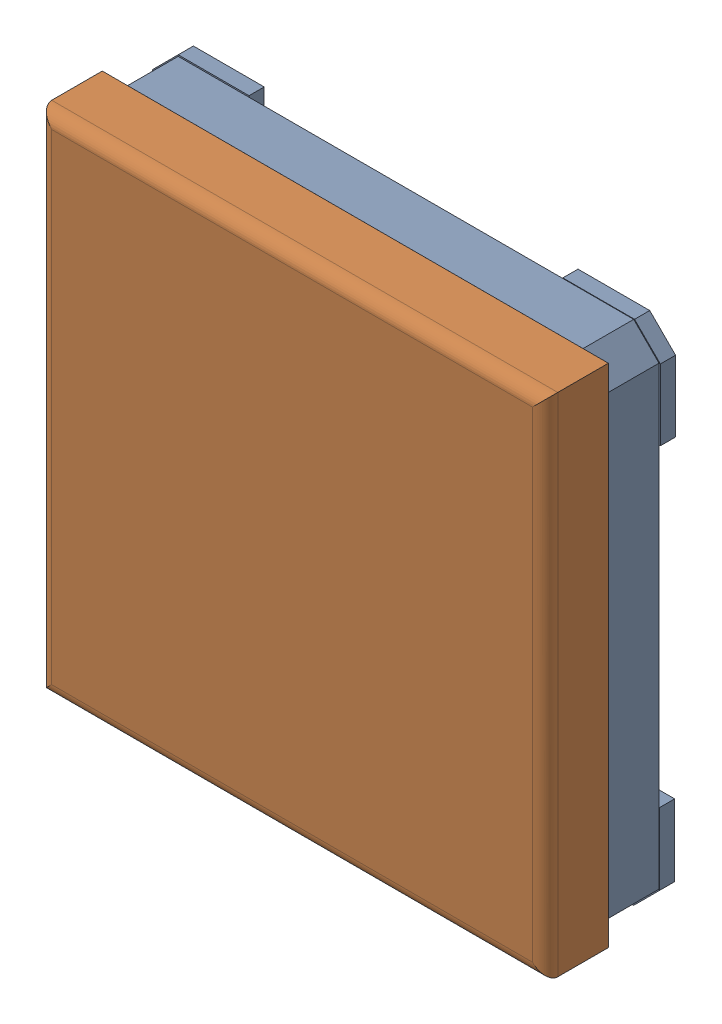
SolidWorks assembly D1, configuration Default. Lengths in mm.
Overall size (1.01 1.01 0.26).
2 component instances, 2 part files, 0 mates.
Components (placement in the parent):
- LUMEX 0404 Base RGB-1: LUMEX 0404 Base RGB [Default] x (0 -1 0) z (0 0 1) size (1.01 1.01 0.15)
- LUMEX 0404 Lens RGB-1: LUMEX 0404 Lens RGB [Default] at (0 0 0) x (0 -1 0) z (0 0 1) size (1 1 0.12)
